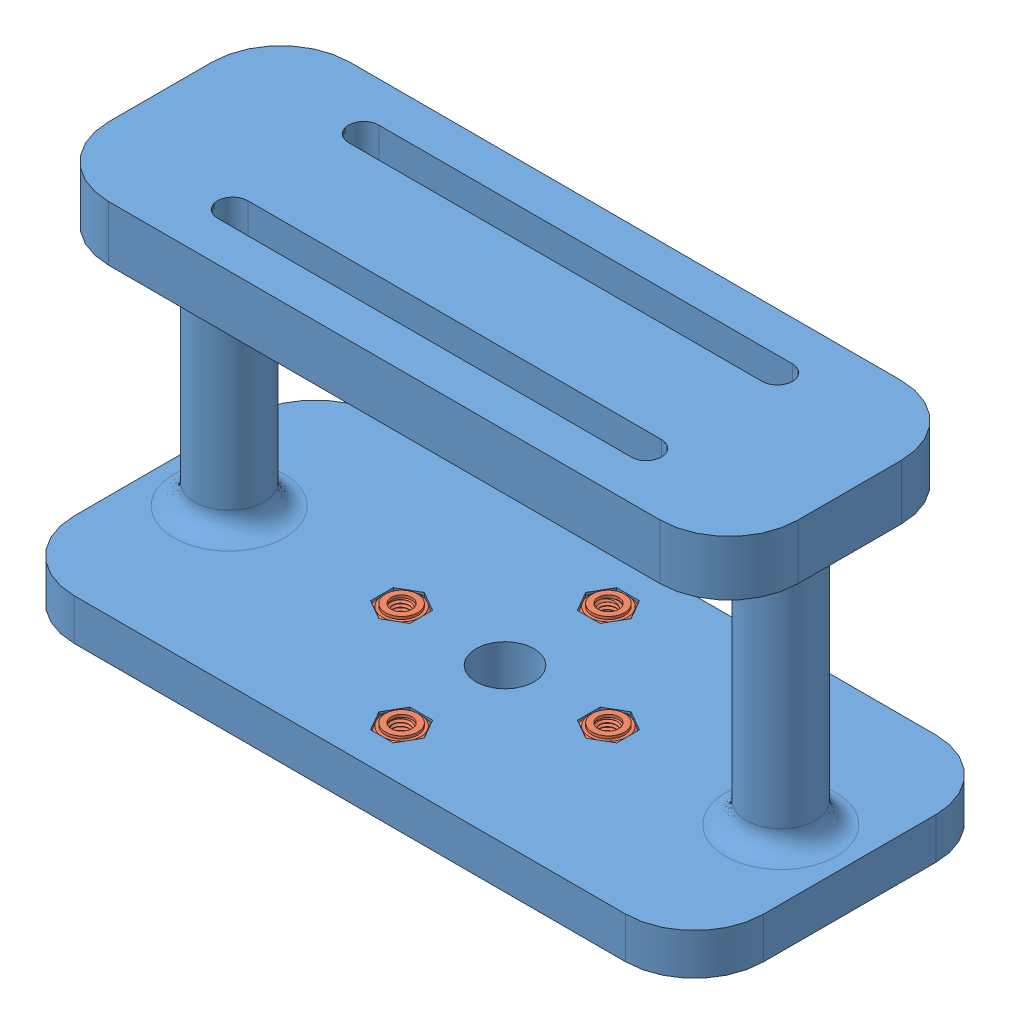
SolidWorks assembly Rectangular_Mounting_Bracket_Assembly, configuration Default. Lengths in mm.
Overall size (100 53 45).
5 component instances, 2 part files, 12 mates.
Components (placement in the parent):
- Rectangular_Mounting_Bracket-1: Rectangular_Mounting_Bracket [Default] at (1.1077 -12.3094 -6.149) size (100 53 45)
- M3 x 0.5 Hex Nut-1: M3 x 0.5 Hex Nut [90592A085] at (-13.8923 -13.6094 -6.149) x (-1 0 0) z (0 0 -1) size (5.5 2.98 6.35)
- M3 x 0.5 Hex Nut-2: M3 x 0.5 Hex Nut [90592A085] at (1.1077 -13.6094 -21.149) x (0.866025 0 -0.5) z (0.5 0 0.866025) size (5.5 2.98 6.35)
- M3 x 0.5 Hex Nut-3: M3 x 0.5 Hex Nut [90592A085] at (16.1077 -13.6094 -6.149) x (-1 0 0) z (0 0 -1) size (5.5 2.98 6.35)
- M3 x 0.5 Hex Nut-4: M3 x 0.5 Hex Nut [90592A085] at (1.1077 -13.6094 8.851) x (-0.866025 0 -0.5) z (0.5 0 -0.866025) size (5.5 2.98 6.35)
Mates (geometry in assembly coordinates):
- Concentric1: concentric: circle of Rectangular_Mounting_Bracket-1; circle of M3 x 0.5 Hex Nut-1
- Concentric3: concentric: circle of Rectangular_Mounting_Bracket-1; circle of M3 x 0.5 Hex Nut-2
- Concentric4: concentric: circle of Rectangular_Mounting_Bracket-1; circle of M3 x 0.5 Hex Nut-4
- Concentric5: concentric: circle of Rectangular_Mounting_Bracket-1; circle of M3 x 0.5 Hex Nut-3
- Parallel1: parallel: plane of Rectangular_Mounting_Bracket-1 through (-13.8923 -14.8094 -9.4399) normal (0.5 0 0.866025); plane of M3 x 0.5 Hex Nut-1 through (-13.8923 -12.4094 -9.3245) normal (-0.5 0 -0.866025)
- Parallel2: parallel: plane of Rectangular_Mounting_Bracket-1 through (-0.5378 -14.8094 -23.999) normal (0.866025 0 0.5); plane of M3 x 0.5 Hex Nut-2 through (2.6954 -12.4094 -18.399) normal (0.866025 0 0.5)
- Parallel3: parallel: plane of Rectangular_Mounting_Bracket-1 through (2.7531 -14.8094 6.001) normal (0 0 1); plane of M3 x 0.5 Hex Nut-4 through (2.6954 -12.4094 6.101) normal (0 0 -1)
- Parallel4: parallel: plane of Rectangular_Mounting_Bracket-1 through (16.1077 -14.8094 -9.4399) normal (0.5 0 0.866025); plane of M3 x 0.5 Hex Nut-3 through (16.1077 -12.4094 -9.3245) normal (-0.5 0 -0.866025)
- Coincident5: coincident anti-aligned: plane of Rectangular_Mounting_Bracket-1 through (1.1077 -14.8094 -6.149) normal (0 1 0); plane of M3 x 0.5 Hex Nut-4 through (2.6954 -14.8094 11.601) normal (0 -1 0)
- Coincident6: coincident anti-aligned: plane of Rectangular_Mounting_Bracket-1 through (1.1077 -14.8094 -6.149) normal (0 1 0); plane of M3 x 0.5 Hex Nut-1 through (-11.1423 -14.8094 -4.5613) normal (0 -1 0)
- Coincident7: coincident anti-aligned: plane of Rectangular_Mounting_Bracket-1 through (1.1077 -14.8094 -6.149) normal (0 1 0); plane of M3 x 0.5 Hex Nut-3 through (18.8577 -14.8094 -4.5613) normal (0 -1 0)
- Coincident8: coincident anti-aligned: plane of Rectangular_Mounting_Bracket-1 through (1.1077 -14.8094 -6.149) normal (0 1 0); plane of M3 x 0.5 Hex Nut-2 through (-2.0678 -14.8094 -21.149) normal (0 -1 0)
